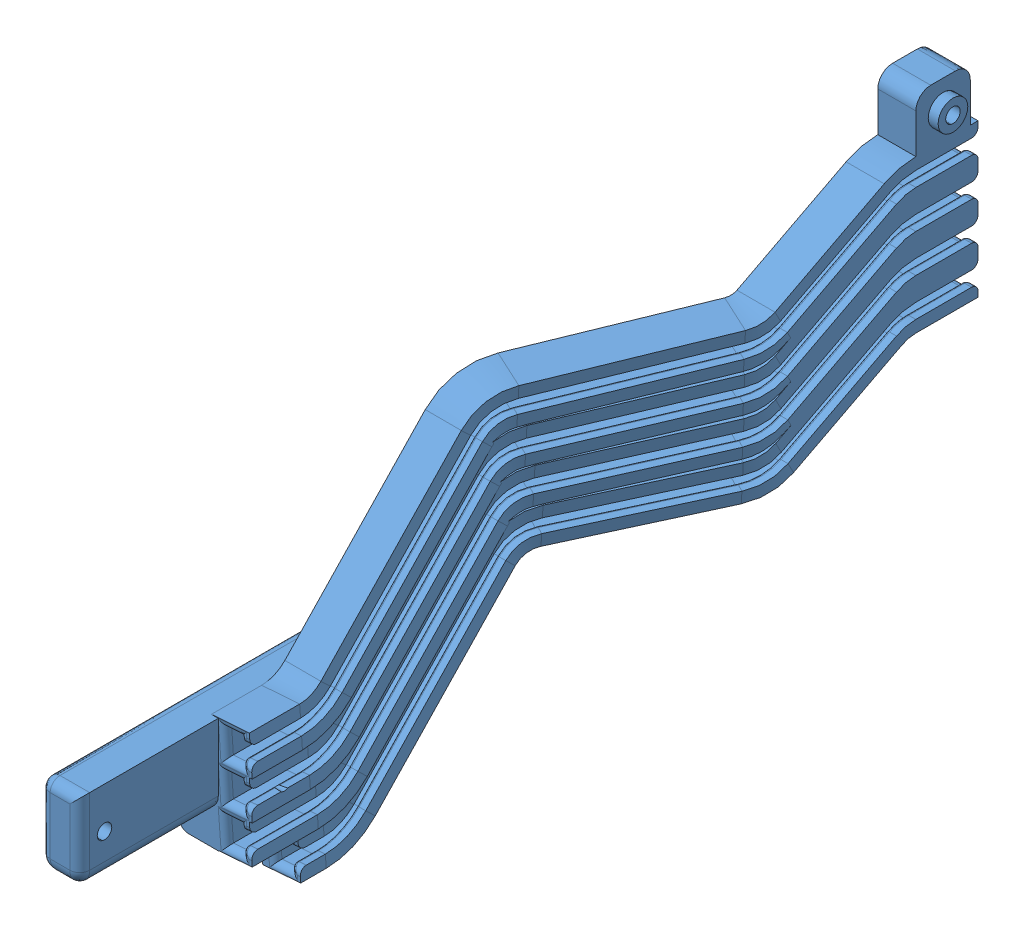
SolidWorks assembly cSL cap guide S5, configuration Default. Lengths in mm.
Overall size (32.76 92.52 158.8).
5 component instances, 2 part files, 4 mates.
Components (placement in the parent):
- cSL cap guides-1: cSL cap guides [51] at origin size (24.17 58.37 130.8) (hidden)
- cSL cap guides-2: cSL cap guides [52] at origin size (24.18 58.39 130.8) (hidden)
- cSL cap guides-3: cSL cap guides [53] at origin size (24.19 58.4 130.8) (hidden)
- cSL cap guides-4: cSL cap guides [54] at origin size (24.2 58.42 121) (hidden)
- cSL cap guide S5^cSL cap guide S5-1: cSL cap guide S5^cSL cap guide S5 [Default] at (-43.3 0 0) x (0 0 -1) z (1 0 0) size (158.8 92.52 32.76) (virtual)
Mates (geometry in assembly coordinates):
- InPlace1: in place: plane of ? through (-43.3 133.6 -652.4384) normal (1 0 0); plane of cSL cap guide S5^cSL cap guide S5-1 through (-43.3 0 0) normal (1 0 0); moOrthogonalPlaneRef_w of ? through (-43.3 133.6 -652.4384) normal (1 0 0); line of cSL cap guide S5^cSL cap guide S5-1 through (-55 -43.3 0) axis (0 0 1); plane of ? through (-43.3 133.6 -652.4384) normal (1 0 0); plane of cSL cap guide S5^cSL cap guide S5-1 through (-43.3 0 0) normal (0 0 -1); plane of ? through (-43.3 133.6 -652.4384) normal (1 0 0); unknown of cSL cap guide S5^cSL cap guide S5-1
- Coincident1: coincident aligned: plane of cSL cap guides-1; plane of cSL cap guide S5^cSL cap guide S5-1
- Coincident2: coincident aligned: moOrthogonalPlaneRef_w of cSL cap guides-1 through (-43.3 0 0) normal (0 1 0); plane of cSL cap guide S5^cSL cap guide S5-1
- Coincident3: coincident anti-aligned: moOrthogonalPlaneRef_w of cSL cap guides-1 through (-43.3 0 0) normal (0 0 1); plane of cSL cap guide S5^cSL cap guide S5-1 through (-43.3 0 0) normal (0 0 -1)
